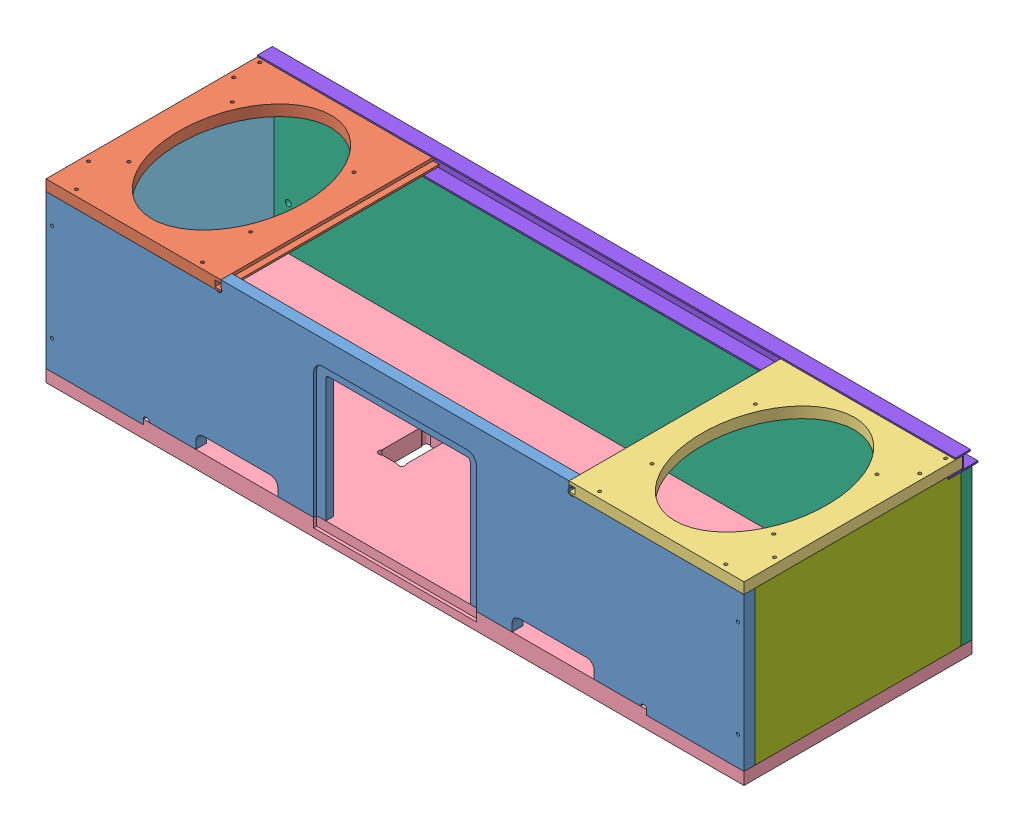
SolidWorks assembly 181226_NewJupiterCrush_Boombox_3, configuration Default. Lengths in mm.
Overall size (728.66 185.67 244.24).
8 component instances, 8 part files, 19 mates.
Components (placement in the parent):
- 190228_NewJupiterCrush_Boombox_4_Bottom-1: 190228_NewJupiterCrush_Boombox_4_Bottom [Thickness_450] at origin size (728.66 171.45 11.43)
- 190301_NewJupiterCrush_Boombox_4_SpeakerLeft-1: 190301_NewJupiterCrush_Boombox_4_SpeakerLeft [Thickness_450] at (-6738.9375 1550.67 5512.5938) x (0 0 1) z (0 1 0) size (227.81 182.56 11.43)
- 181226_NewJupiterCrush_Boombox_3_SpeakerRight-1: 181226_NewJupiterCrush_Boombox_3_SpeakerRight [Thickness_450] at (-6192.8375 1550.67 5258.5938) x (0 0 1) z (0 1 0) size (227.81 182.56 11.43)
- 190302_NewJupiterCrush_Boombox_4_Back-1: 190302_NewJupiterCrush_Boombox_4_Back [Thickness_700] at (-10752.1375 1366.52 660.4) x (-1 0 0) z (0 -1 0) size (728.66 238.13 17.78)
- 190301_NewJupiterCrush_Boombox_1_SideLeft-2: 190301_NewJupiterCrush_Boombox_1_SideLeft [Thickness_450] at (-5728.97 160.02 -4989.83) x (0 0 -1) z (1 0 0) size (215.26 160.02 11.43)
- 181226_NewJupiterCrush_Boombox_3_Top-1: 181226_NewJupiterCrush_Boombox_3_Top [Thickness_450] at (-10752.1375 2742.8825 -226.695) x (-1 0 0) z (0 0 1) size (728.66 157.16 11.43)
- 190301_NewJupiterCrush_Boombox_1_SideRight-1: 190301_NewJupiterCrush_Boombox_1_SideRight [Thickness_450] at (-5023.1675 160.02 4754.245) x (0 0 1) z (-1 0 0) size (215.27 160.02 11.43)
- 190303_Boombox_Backglass_Channel_1-1: 190303_Boombox_Backglass_Channel_1 [Default] at (-5376.0688 1595.12 -228.5683) x (0 -1 0) z (1 0 0) size (15.75 31.34 728.66)
Mates (geometry in assembly coordinates):
- Coincident1: coincident anti-aligned: plane of ?; plane of ?
- Coincident2: coincident aligned: plane of ?; plane of ?
- Coincident3: coincident aligned: plane of ?; plane of ?
- Coincident4: coincident anti-aligned: plane of ?; plane of ?
- Coincident5: coincident aligned: plane of ?; plane of ?
- Coincident6: coincident aligned: plane of ?; plane of ?
- Coincident7: coincident anti-aligned: plane of ?; plane of ?
- Coincident8: coincident aligned: plane of ?; plane of ?
- Coincident9: coincident aligned: plane of ?; plane of ?
- Coincident15: coincident aligned: plane of ?; plane of ?
- Coincident17: coincident aligned: plane of ?; plane of ?
- Coincident18: coincident anti-aligned: plane of ?; plane of ?
- Coincident19: coincident aligned: plane of ?; plane of ?
- Coincident20: coincident anti-aligned: plane of ?; plane of ?
- Coincident22: coincident anti-aligned: plane of ?; plane of ?
- Coincident23: coincident aligned: plane of ?; plane of ?
- Coincident24: coincident anti-aligned: unknown of 190303_Boombox_Backglass_Channel_1-1
- Coincident25: coincident anti-aligned: unknown of 190303_Boombox_Backglass_Channel_1-1
- Coincident29: coincident: point of 190303_Boombox_Backglass_Channel_1-1
